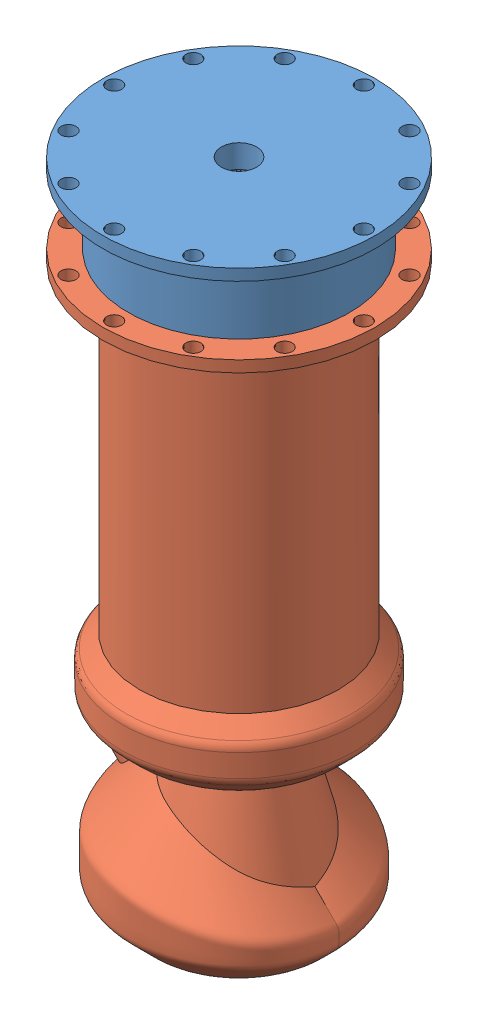
SolidWorks assembly regen additive coax swirl engine, configuration Default. Lengths in mm.
Overall size (152.4 407.94 152.4).
2 component instances, 2 part files, 4 mates.
Components (placement in the parent):
- addative coax swirl injector3-1: addative coax swirl injector3 [Default] at (0 44.45 0) size (152.4 50.8 152.4)
- slot cooling jacket 11-1: slot cooling jacket 11 [Default] at origin size (152.4 363.49 152.4)
Mates (geometry in assembly coordinates):
- Coincident1: coordinate: point of slot cooling jacket 11-1
- Concentric1: concentric aligned: cylinder of addative coax swirl injector3-1 through (0 -6.35 0) axis (0 -1 0) radius 46.0375; cylinder of slot cooling jacket 11-1 through (0 0 0) axis (0 -1 0) radius 46.0375
- Coincident2: coincident anti-aligned: plane of addative coax swirl injector3-1 through (-61.9125 0 0) normal (0 -1 0); plane of slot cooling jacket 11-1 through (-46.0375 0 0) normal (0 1 0)
- Concentric2: concentric aligned: cylinder of addative coax swirl injector3-1 through (69.85 44.45 0) axis (0 1 0) radius 4.2164; cylinder of slot cooling jacket 11-1 through (69.85 0 0) axis (0 1 0) radius 4.2164
